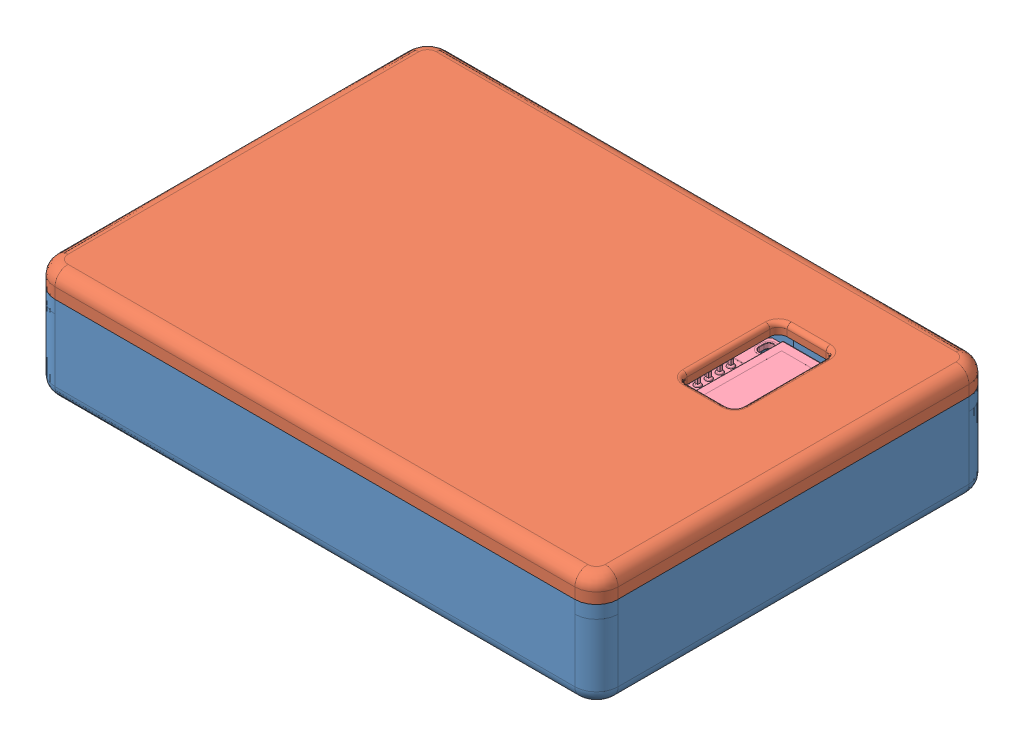
SolidWorks assembly Assem1_new, configuration Default. Lengths in mm.
Overall size (130.04 25.96 91).
4 component instances, 4 part files, 7 mates.
Components (placement in the parent):
- Part1-1: Part1 [Default] at (42.7681 -36.1332 -85.4625) size (130 20.5 91)
- Part2-1: Part2 [Default] at (42.7681 -10.1768 5.5375) x (1 0 0) z (0 -1 0) size (130 91 20.5)
- PCB2_2.step-2: PCB2_2.step [Default] at (-6.4569 -27.0095 0.3875) x (1 0 0) z (0 1 0) size (84.85 39.24 11.62)
- STEP OLED_new-1: STEP OLED_new [Default] at (149.548 -18.5247 -56.982) x (0.008727 0 -0.999962) z (-0.008726 0.999962 -0.000076) size (28.4 27.4 11)
Mates (geometry in assembly coordinates):
- Concentric1: concentric aligned: circle of Part1-1; circle of PCB2_2.step-2
- Coincident4: coincident aligned: plane of Part1-1 through (52.0681 -27.6332 -74.8825) normal (0 1 0); circle of PCB2_2.step-2
- Coincident5: coincident aligned: plane of Part1-1 through (123.9381 -27.6332 -43.2325) normal (0 1 0); circle of PCB2_2.step-2
- Coincident6: coincident aligned: plane of Part1-1 through (52.0681 -27.6332 -43.2325) normal (0 1 0); circle of PCB2_2.step-2
- Coincident7: coincident aligned: plane of Part1-1 through (123.9381 -27.6332 -74.8825) normal (0 1 0); circle of PCB2_2.step-2
- Parallel4: parallel anti-aligned: line of Part1-1 through (167.7681 -15.6332 -85.4625) axis (-1 0 0); line of Part2-1 through (47.7681 -13.1768 -85.4625) axis (1 0 0)
- Concentric4: concentric aligned: cylinder of Part1-1 through (145.2681 -31.6332 -14.9625) axis (0 1 0) radius 1.5; cylinder of Part2-1 through (145.2681 -30.6768 -14.9625) axis (0 1 0) radius 1.4
